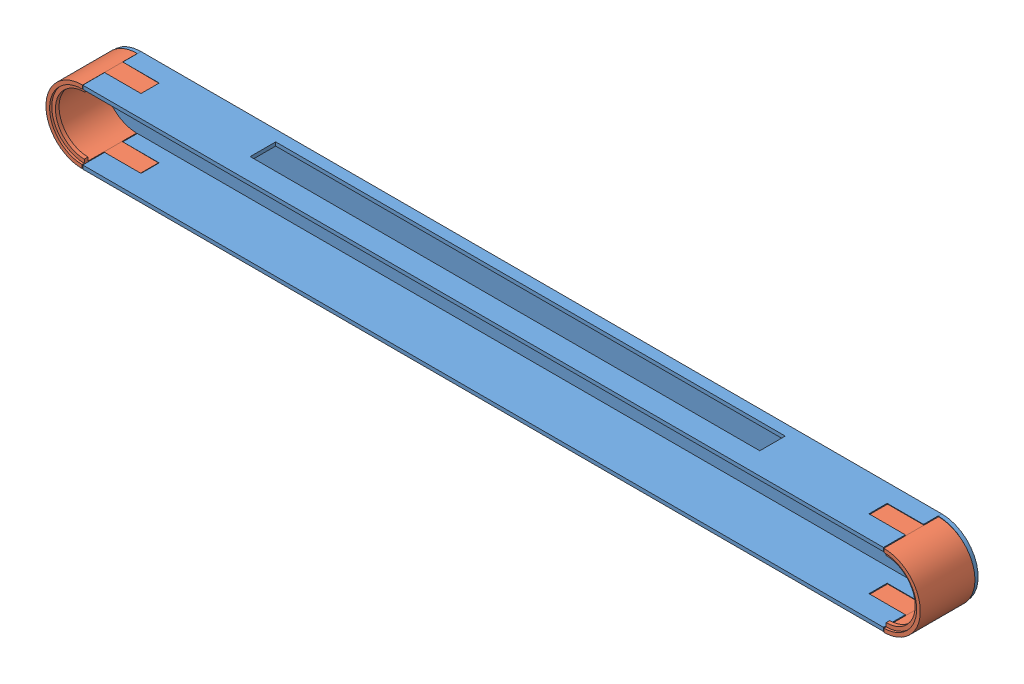
SolidWorks assembly Assem2, configuration Default. Lengths in mm.
Overall size (1202.1 100.87 80.54).
3 component instances, 2 part files, 0 mates.
Components (placement in the parent):
- joint-1: joint [Default] at (110.605 681.9741 1061.2286) size (1200 100 80)
- joint-sides-1: joint-sides [Default] at (111.6703 681.7797 1061.7665) size (100 100 75)
- joint-sides-2: joint-sides [Default] at (204.5105 676.7621 1061.204) x (-0.999962 0.008727 0) z (0 0 1) size (100 100 75)
